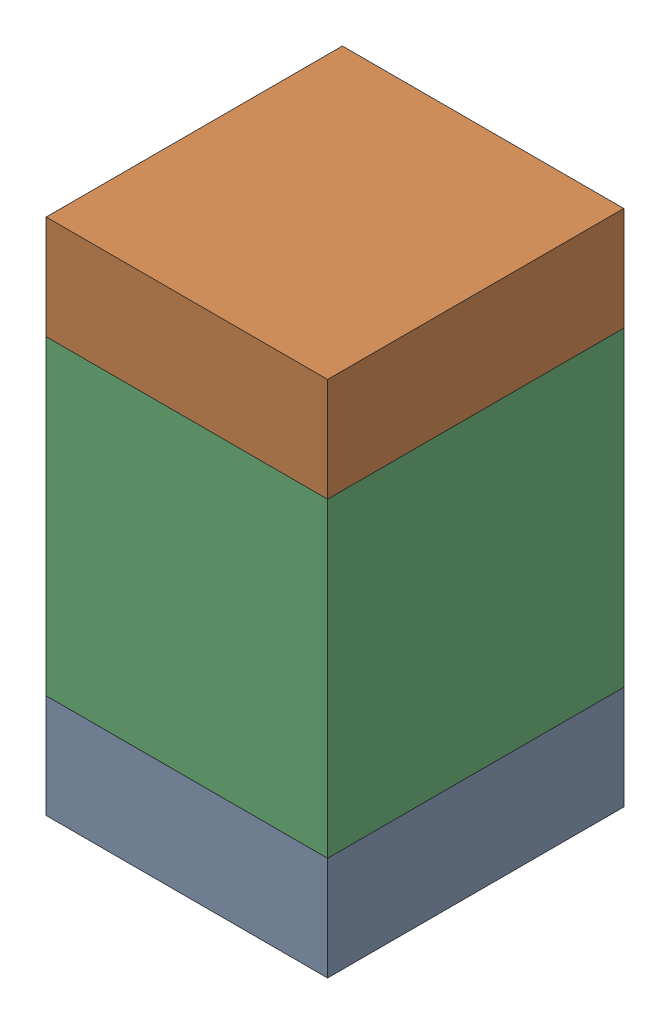
SolidWorks assembly C3, configuration Default. Lengths in mm.
Overall size (0.95 1.75 1).
6 component instances, 2 part files, 0 mates.
Components (placement in the parent):
- 959208664-1: 959208664 [Default] at (146.558 83.0961 0) size (0.95 0.35 1)
  - Extruded-14-1: Extruded-14 [Default] at origin size (0.95 0.35 1)
- 959208664-2: 959208664 [Default] at (146.558 84.4961 0) size (0.95 0.35 1)
  - Extruded-14-1: Extruded-14 [Default] at origin size (0.95 0.35 1)
- 959208528-1: 959208528 [Default] at (146.558 83.7961 0) size (0.95 1.05 1)
  - Extruded-15-1: Extruded-15 [Default] at origin size (0.95 1.05 1)
